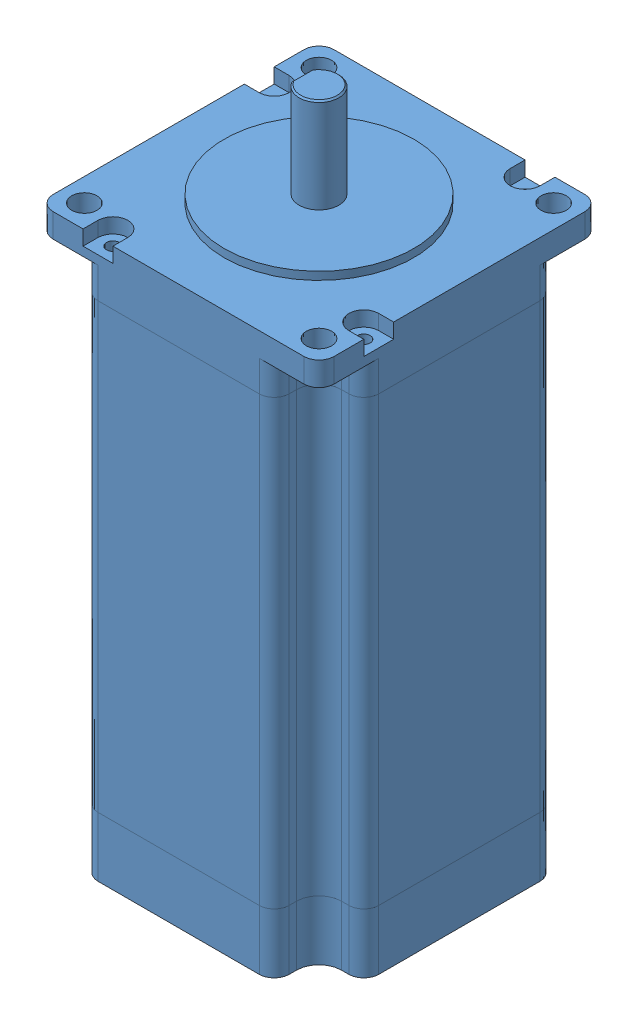
SolidWorks assembly Сборка3, configuration По умолчанию. Lengths in mm.
Overall size (56.4 132.6 56.4).
2 component instances, 1 part files, 3 mates.
Components (placement in the parent):
- Деталь7-1: Деталь7 [По умолчанию] at origin size (56.4 120.6 56.4)
- Деталь7-2: Деталь7 [1] at (0 -36 0) size (56.4 12 56.4)
Mates (geometry in assembly coordinates):
- Концентричный1: concentric: cylinder of Деталь7-1 through (16.2 -89 -25.2) axis (0 1 0) radius 1.3; cylinder of Деталь7-2 through (16.2 -17.7085 -25.2) axis (0 -1 0) radius 1.3
- Концентричный2: concentric: cylinder of Деталь7-1 through (-16.2 -89 25.2) axis (0 1 0) radius 1.3; cylinder of Деталь7-2 through (-16.2 -17.7085 25.2) axis (0 -1 0) radius 1.3
- Совпадение1: coincident anti-aligned: plane of Деталь7-1 through (16.2 -89 25.2) normal (0 -1 0); plane of Деталь7-2 through (16.2 -89 25.2) normal (0 1 0)
